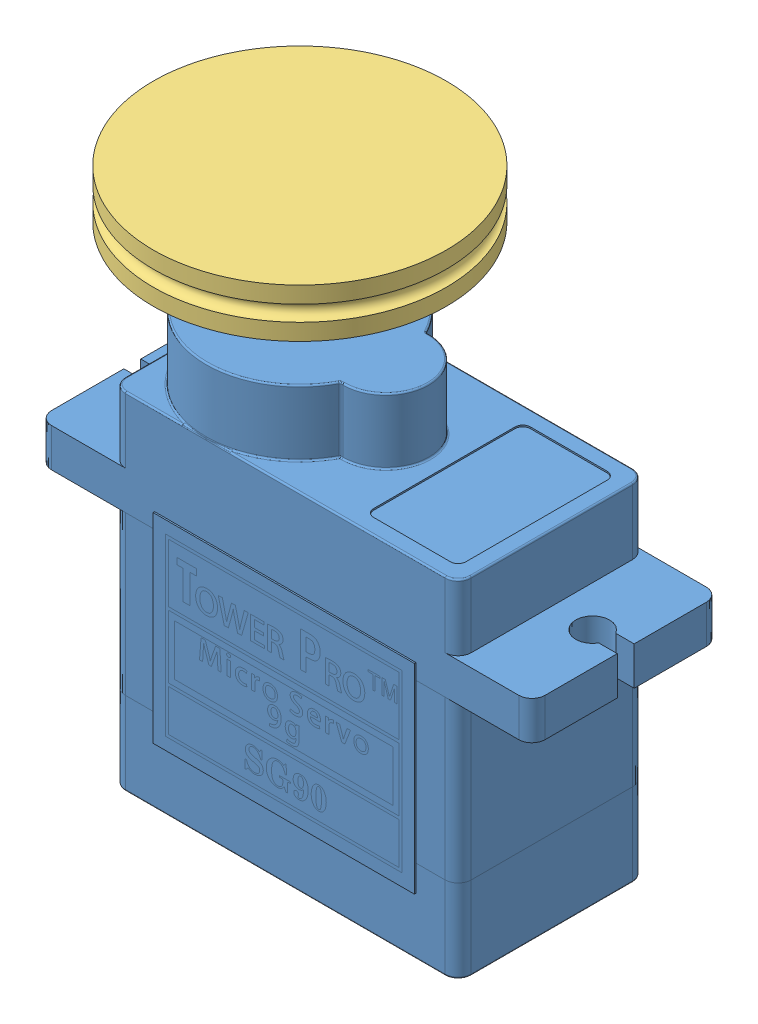
SolidWorks assembly servo-spinner-combo, configuration Default. Lengths in mm.
Overall size (32.1 34.93 19.05).
3 component instances, 3 part files, 4 mates.
Components (placement in the parent):
- SG90 - Micro Servo 9g - Tower Pro.1-1: SG90 - Micro Servo 9g - Tower Pro.1 [Peça] at (12.6007 11.4301 24.99) size (32.1 29.95 12.4)
- SG90 - Micro Servo 9g - Tower Pro.3-1: SG90 - Micro Servo 9g - Tower Pro.3 [Peça] at (7.4507 32.5301 24.99) x (0.379808 0 -0.925065) z (0.925065 0 0.379808) size (14.96 3.8 6.9)
- fishing-line-spinner-375-1: fishing-line-spinner-375 [Default] at (7.4507 32.5301 24.99) size (19.05 3.17 19.05)
Mates (geometry in assembly coordinates):
- Coincident1: coincident: plane of SG90 - Micro Servo 9g - Tower Pro.1-1 through (7.4507 30.7301 24.99) normal (0 1 0); plane of SG90 - Micro Servo 9g - Tower Pro.3-1 through (7.4507 30.7301 24.99) normal (0 -1 0)
- Concentric1: concentric: cylinder of SG90 - Micro Servo 9g - Tower Pro.1-1 through (7.4507 27.6301 24.99) axis (0 -1 0) radius 6.1; cylinder of SG90 - Micro Servo 9g - Tower Pro.3-1 through (7.4507 31.1301 24.99) axis (0 1 0) radius 3.45
- Coincident2: coincident: plane of SG90 - Micro Servo 9g - Tower Pro.3-1 through (7.4507 32.5301 24.99) normal (0 1 0); plane of fishing-line-spinner-375-1 through (7.4507 32.5301 24.99) normal (0 -1 0)
- Concentric2: concentric: cylinder of SG90 - Micro Servo 9g - Tower Pro.3-1 through (7.4507 32.5301 24.99) axis (0 1 0) radius 2.3; cylinder of fishing-line-spinner-375-1 through (7.4507 35.7051 24.99) axis (0 -1 0) radius 9.525
